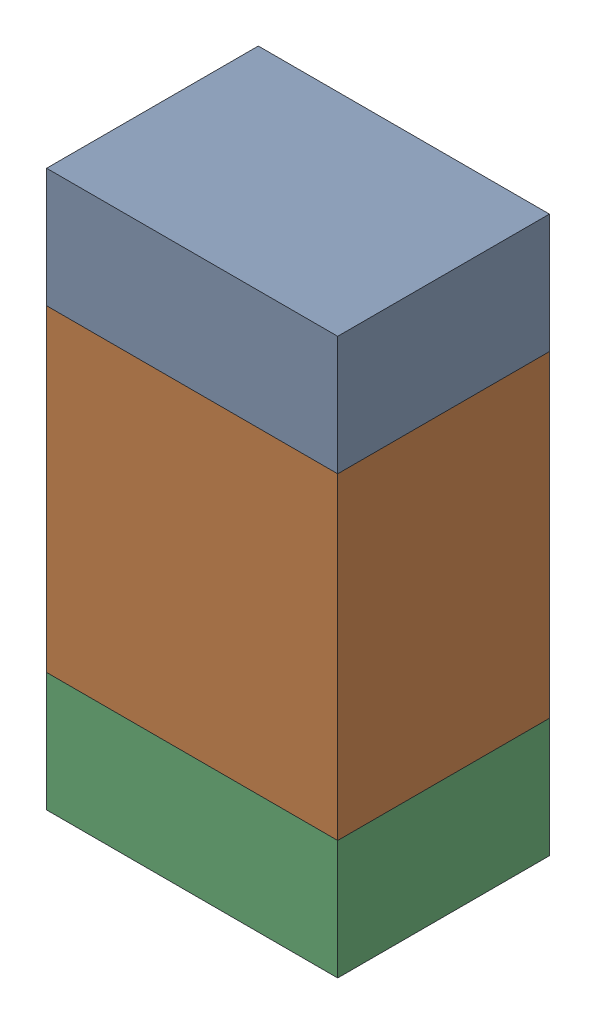
SolidWorks assembly R316_1PCB, configuration Default. Lengths in mm.
Overall size (0.55 1.05 0.4).
6 component instances, 2 part files, 0 mates.
Components (placement in the parent):
- 846483288-1: 846483288 [Default] at (128.5001 109.0126 -2.0638) size (0.55 0.22 0.4)
  - Extruded_12-1: Extruded_12 [Default] at origin size (0.55 0.22 0.4)
- 846483424-1: 846483424 [Default] at (128.5001 108.6001 -2.0638) size (0.55 0.6 0.4)
  - Extruded_13-1: Extruded_13 [Default] at origin size (0.55 0.6 0.4)
- 846483288-2: 846483288 [Default] at (128.5001 108.1876 -2.0638) size (0.55 0.22 0.4)
  - Extruded_12-1: Extruded_12 [Default] at origin size (0.55 0.22 0.4)
